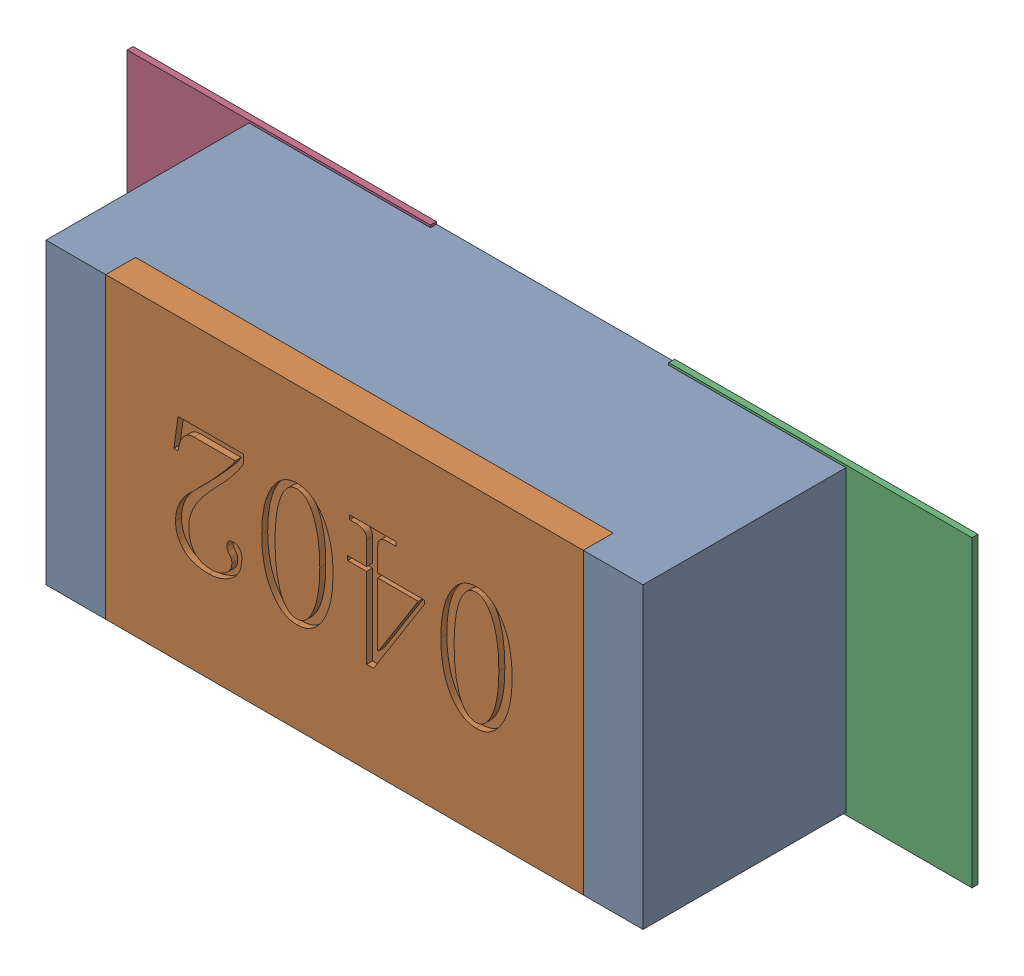
SolidWorks assembly R149, configuration Défaut. Lengths in mm.
Overall size (1.42 0.51 0.35).
5 component instances, 2 part files, 0 mates.
Components (placement in the parent):
- R0402-1: R0402 [Défaut] at (12.2865 -25.3533 0) x (-1 0 0) z (0 0 1) size (1 0.5 0.35)
- 6504207776-1: 6504207776 [Défaut] at (12.7436 -25.3535 0) size (0.51 0.51 0.01)
  - Extruded-1: Extruded [Défaut] at origin size (0.51 0.51 0.01)
- 6504207776-2: 6504207776 [Défaut] at (11.8365 -25.3535 0) size (0.51 0.51 0.01)
  - Extruded-1: Extruded [Défaut] at origin size (0.51 0.51 0.01)
